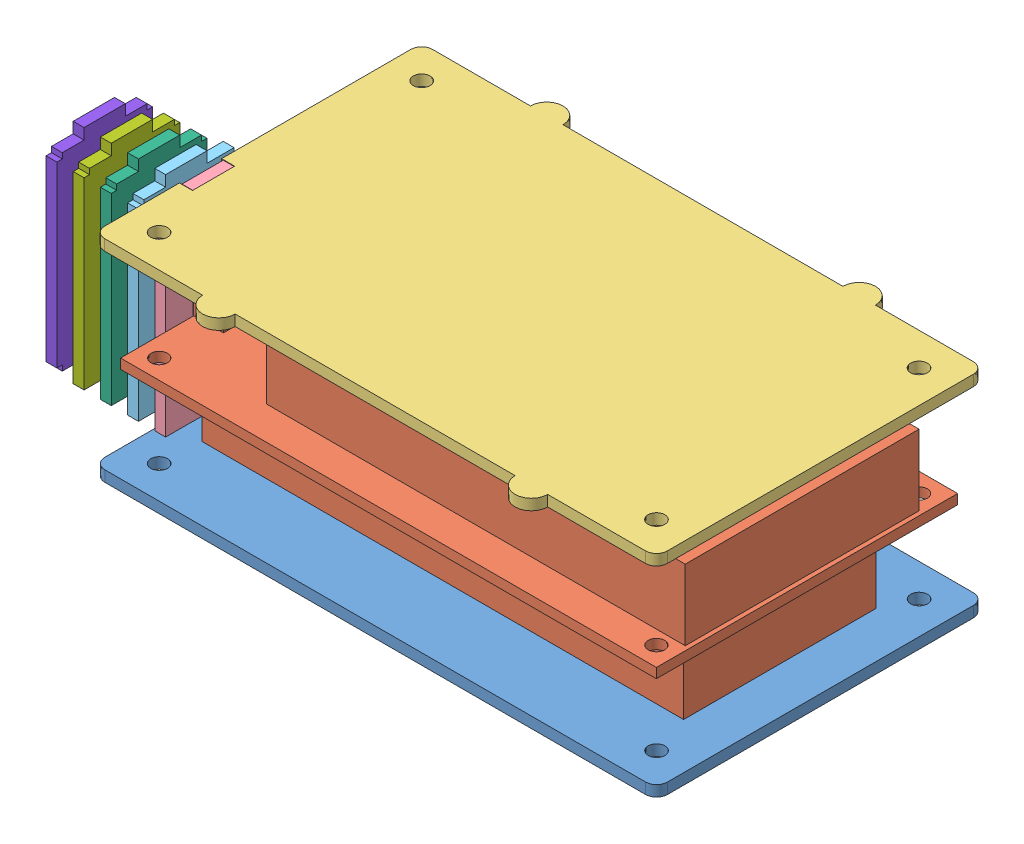
SolidWorks assembly assembly, configuration 默认. Lengths in mm.
Overall size (123.08 38.8 66.29).
8 component instances, 8 part files, 19 mates.
Components (placement in the parent):
- back-1: back [默认] at (-48.1316 -1.3602 24.145) size (103.46 2 60.29)
- main_board-1: main_board [默认] at (-51.6876 15.6398 27.701) size (98.55 31.8 55.4)
- front-1: front [默认] at (-48.1516 35.4398 24.145) size (103.46 2 66.29)
- side-1: side [默认] at (-51.7516 0.6398 1.745) x (0 0 1) z (0 -1 0) size (17.6 2 38.8)
- side_2-1: side_2 [默认] at (-58.7516 0.6398 19.345) x (0 0 -1) z (0 -1 0) size (17.6 2 38.8)
- side_3-1: side_3 [默认] at (-63.7516 0.6398 19.345) x (0 0 -1) z (0 -1 0) size (17.6 2 38.8)
- side_4-1: side_4 [默认] at (-68.7516 0.6398 19.345) x (0 0 -1) z (0 -1 0) size (17.6 2 38.8)
- side_5-1: side_5 [默认] at (-73.7516 0.6398 19.345) x (0 0 -1) z (0 -1 0) size (17.6 2 38.8)
Mates (geometry in assembly coordinates):
- 同心1: concentric aligned: circle of front_and_back-1; circle of main_board-1
- 距离1: distance = 1 mm: plane of front_and_back-1 through (-48.1316 0.6398 24.145) normal (0 1 0); line of main_board-1 through (41.8624 1.6398 17.701) axis (-1 0 0)
- 同心3: concentric aligned: circle of main_board-1; circle of front-1
- 距离3: distance = 18 mm anti-aligned: plane of front-1 through (-48.1516 35.4398 24.145) normal (0 -1 0); plane of main_board-1 through (-51.6876 17.4398 27.701) normal (0 1 0)
- 重合5: coincident aligned: plane of front-1 through (-48.1516 37.4398 24.145) normal (0 1 0); plane of side-1 through (-53.7516 37.4398 1.745) normal (0 1 0)
- 距离4: distance = 10.8 mm aligned: plane of side-1 through (-53.7516 0.6398 19.345) normal (0 0 1); plane of front-1 through (-48.1516 37.4398 30.145) normal (0 0 1)
- 重合7: coincident anti-aligned: plane of front-1 through (-51.7516 37.4398 24.145) normal (-1 0 0); plane of side-1 through (-51.7516 0.6398 1.745) normal (1 0 0)
- 重合8: coincident aligned: plane of side-1 through (-53.7516 37.4398 1.745) normal (0 1 0); plane of side_2-1 through (-56.7516 37.4398 19.345) normal (0 1 0)
- 重合9: coincident aligned: plane of side-1 through (-53.7516 0.6398 19.345) normal (0 0 1); plane of side_2-1 through (-56.7516 0.6398 19.345) normal (0 0 1)
- 距离5: distance = 5 mm aligned: plane of side_2-1 through (-58.7516 0.6398 19.345) normal (-1 0 0); plane of side-1 through (-53.7516 0.6398 1.745) normal (-1 0 0)
- 重合11: coincident aligned: plane of side_2-1 through (-56.7516 0.6398 19.345) normal (0 0 1); plane of side_3-1 through (-61.7516 0.6398 19.345) normal (0 0 1)
- 重合12: coincident aligned: plane of side-1 through (-53.7516 37.4398 1.745) normal (0 1 0); plane of side_3-1 through (-61.7516 37.4398 19.345) normal (0 1 0)
- 距离6: distance = 5 mm aligned: plane of side_3-1 through (-61.7516 0.6398 19.345) normal (1 0 0); plane of side_2-1 through (-56.7516 0.6398 19.345) normal (1 0 0)
- 重合14: coincident aligned: plane of side_3-1 through (-61.7516 0.6398 19.345) normal (0 0 1); plane of side_4-1 through (-66.7516 0.6398 19.345) normal (0 0 1)
- 重合15: coincident aligned: plane of side_2-1 through (-56.7516 37.4398 19.345) normal (0 1 0); plane of side_4-1 through (-66.7516 37.4398 19.345) normal (0 1 0)
- 距离7: distance = 5 mm aligned: plane of side_4-1 through (-66.7516 0.6398 19.345) normal (1 0 0); plane of side_3-1 through (-61.7516 0.6398 19.345) normal (1 0 0)
- 重合17: coincident aligned: plane of side_4-1 through (-66.7516 0.6398 19.345) normal (0 0 1); plane of side_5-1 through (-71.7516 0.6398 19.345) normal (0 0 1)
- 重合18: coincident aligned: plane of side_3-1 through (-61.7516 37.4398 19.345) normal (0 1 0); plane of side_5-1 through (-71.7516 37.4398 19.345) normal (0 1 0)
- 距离8: distance = 5 mm aligned: plane of side_5-1 through (-71.7516 0.6398 19.345) normal (1 0 0); plane of side_4-1 through (-66.7516 0.6398 19.345) normal (1 0 0)
